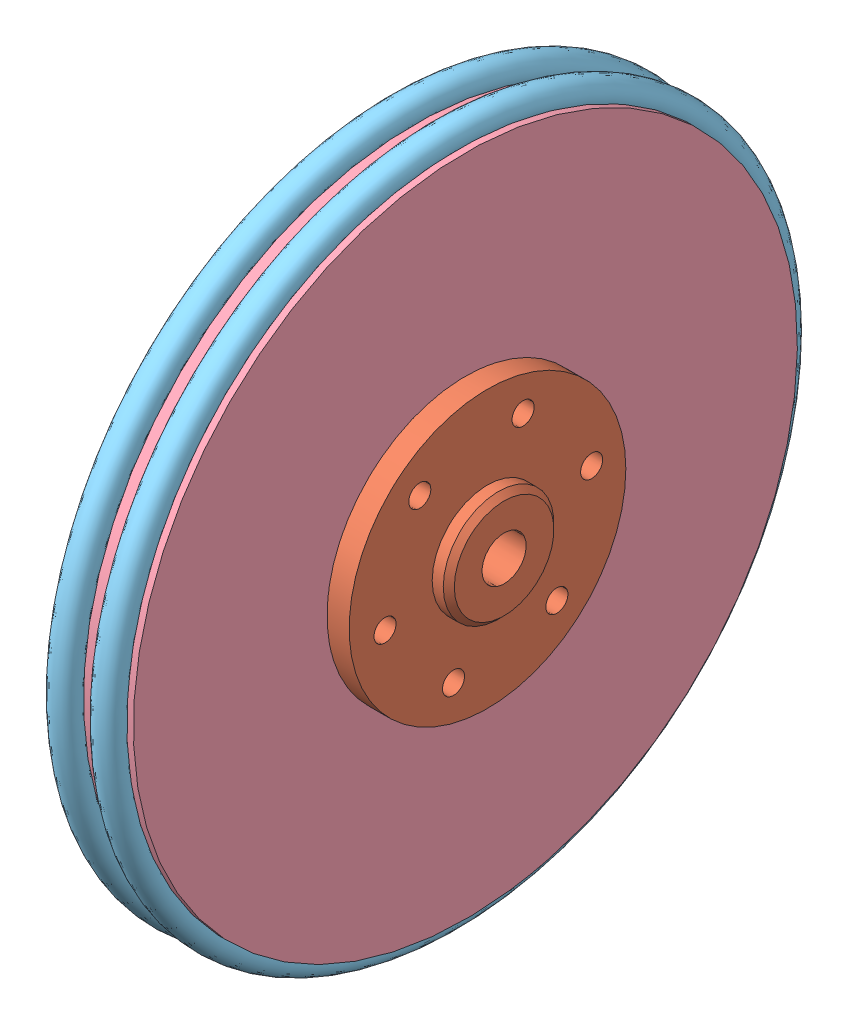
SolidWorks assembly robot_Assem1, configuration Default. Lengths in mm.
Overall size (33.89 140.98 140.98).
6 component instances, 5 part files, 6 mates.
Components (placement in the parent):
- Base_Stand_1-1: Base_Stand_1 [Default] at (-7.6098 18.097 61.6329) size (22.5 53 53)
- Base_Stand_2-1: Base_Stand_2 [Default] at (10.0271 18.097 61.6329) x (1 0 0) z (0 -0.759057 -0.651025) size (30 50 50)
- bearing_1-1: bearing_1 [Default] at (-1.8598 18.097 61.6329) x (1 0 0) z (0 0.444378 0.895839) size (6 18 18)
- Wheels-3: Wheels [Default] at (0.5271 18.097 61.6329) x (-1 0 0) z (0 0.981038 0.193815) size (15 120 120)
- Rubber-1: Rubber [Default] at (-3.4293 18.097 61.6329) x (0 0.002151 -0.999998) z (1 0 0) size (126.5 126.5 5)
- Rubber-4: Rubber [Default] at (4.4835 18.097 61.6329) x (0 0.002151 -0.999998) z (1 0 0) size (126.5 126.5 5)
Mates (geometry in assembly coordinates):
- Concentric16: concentric anti-aligned: circle of Base_Stand_2-1; circle of Wheels-3
- Coincident20: coincident anti-aligned: plane of Base_Stand_2-1 through (5.0271 18.097 61.6329) normal (-1 0 0); plane of Wheels-3 through (5.0271 18.097 61.6329) normal (1 0 0)
- Concentric19: concentric anti-aligned: cylinder of Base_Stand_2-1; cylinder of bearing_1-1 through (-4.8598 18.097 61.6329) axis (1 0 0) radius 6
- Concentric20: concentric aligned: cylinder of Base_Stand_1-1 through (1.1402 18.097 61.6329) axis (-1 0 0) radius 9; cylinder of bearing_1-1 through (1.1402 18.097 61.6329) axis (-1 0 0) radius 9
- Coincident22: coincident anti-aligned: plane of Base_Stand_1-1 through (1.1402 18.097 61.6329) normal (-1 0 0); plane of bearing_1-1 through (1.1402 18.097 61.6329) normal (1 0 0)
- Concentric23: concentric anti-aligned: circle of Wheels-3; circle of Rubber-1
